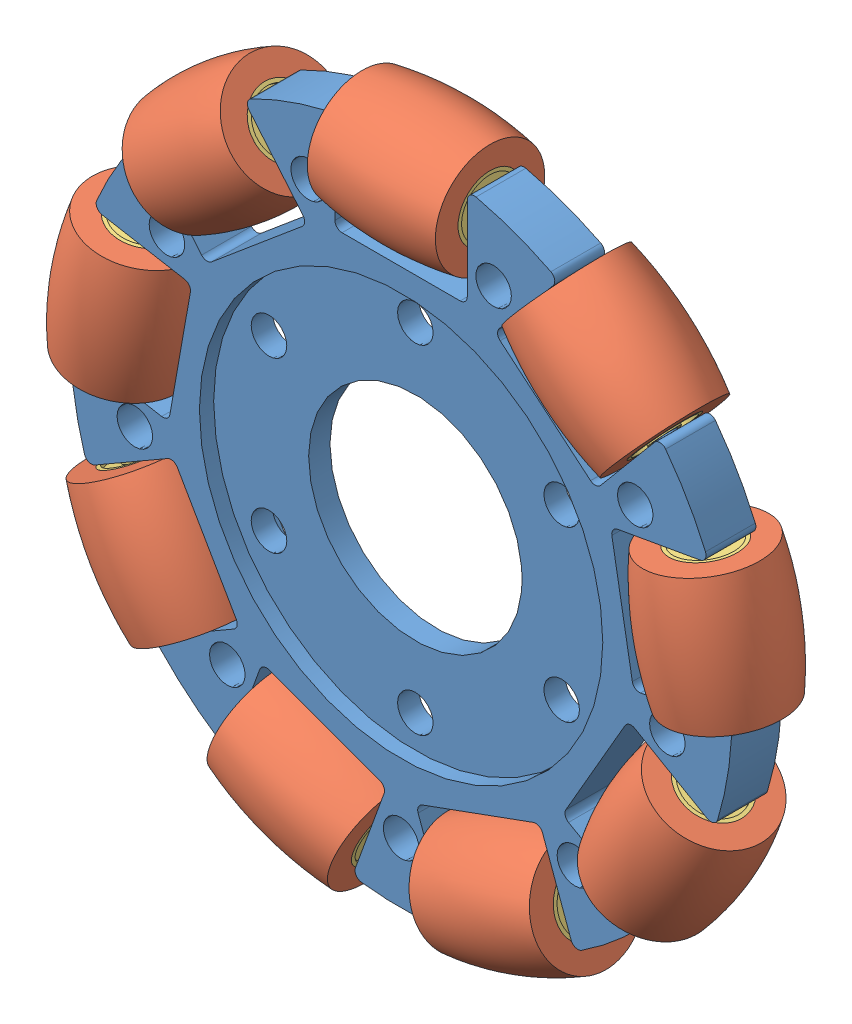
SolidWorks assembly Single Side, configuration Default. Lengths in mm.
Overall size (107.72 106.08 23.21).
28 component instances, 3 part files, 4 mates.
Components (placement in the parent):
- Frame-1: Frame [Default] at origin size (92.88 91.83 7)
- Roller_New-1: Roller_New [預設] at (0 41.5 0) x (1 0 0) z (0 -0.498092 0.867124) size (18 17 17)
- MR93zz_3x9x4mm-1: MR93zz_3x9x4mm [預設] at (7 41.5 0) x (0 0 -1) z (1 0 0) size (9 9 4)
- MR93zz_3x9x4mm-2: MR93zz_3x9x4mm [預設] at (-7 41.5 0) x (0 0 1) z (-1 0 0) size (9 9 4)
- Roller_New-2: Roller_New [預設] at (-26.6757 31.7908 0) x (0.766044 0.642788 0) z (0.320168 -0.381561 0.867124) size (18 17 17)
- Roller_New-3: Roller_New [預設] at (-40.8695 7.2064 0) x (0.173648 0.984808 0) z (0.490525 -0.086493 0.867124) size (18 17 17)
- Roller_New-4: Roller_New [預設] at (-35.9401 -20.75 0) x (-0.5 0.866025 0) z (0.431361 0.249046 0.867124) size (18 17 17)
- Roller_New-5: Roller_New [預設] at (-14.1938 -38.9972 0) x (-0.939693 0.34202 0) z (0.170358 0.468054 0.867124) size (18 17 17)
- Roller_New-6: Roller_New [預設] at (14.1938 -38.9972 0) x (-0.939693 -0.34202 0) z (-0.170358 0.468054 0.867124) size (18 17 17)
- Roller_New-7: Roller_New [預設] at (35.9401 -20.75 0) x (-0.5 -0.866025 0) z (-0.431361 0.249046 0.867124) size (18 17 17)
- Roller_New-8: Roller_New [預設] at (40.8695 7.2064 0) x (0.173648 -0.984808 0) z (-0.490525 -0.086493 0.867124) size (18 17 17)
- Roller_New-9: Roller_New [預設] at (26.6757 31.7908 0) x (0.766044 -0.642788 0) z (-0.320168 -0.381561 0.867124) size (18 17 17)
- MR93zz_3x9x4mm-3: MR93zz_3x9x4mm [預設] at (-32.038 27.2913 0) x (0 0 1) z (-0.766044 -0.642788 0) size (9 9 4)
- MR93zz_3x9x4mm-4: MR93zz_3x9x4mm [預設] at (-42.0851 0.3127 0) x (0 0 1) z (-0.173648 -0.984808 0) size (9 9 4)
- MR93zz_3x9x4mm-5: MR93zz_3x9x4mm [預設] at (-32.4401 -26.8122 0) x (0 0 1) z (0.5 -0.866025 0) size (9 9 4)
- MR93zz_3x9x4mm-6: MR93zz_3x9x4mm [預設] at (-7.616 -41.3914 0) x (0 0 1) z (0.939693 -0.34202 0) size (9 9 4)
- MR93zz_3x9x4mm-7: MR93zz_3x9x4mm [預設] at (20.7717 -36.6031 0) x (0 0 1) z (0.939693 0.34202 0) size (9 9 4)
- MR93zz_3x9x4mm-8: MR93zz_3x9x4mm [預設] at (39.4401 -14.6878 0) x (0 0 1) z (0.5 0.866025 0) size (9 9 4)
- MR93zz_3x9x4mm-9: MR93zz_3x9x4mm [預設] at (39.654 14.1001 0) x (0 0 1) z (-0.173648 0.984808 0) size (9 9 4)
- MR93zz_3x9x4mm-10: MR93zz_3x9x4mm [預設] at (21.3134 36.2904 0) x (0 0 1) z (-0.766044 0.642788 0) size (9 9 4)
- MR93zz_3x9x4mm-11: MR93zz_3x9x4mm [預設] at (-21.3134 36.2904 0) x (0 0 -1) z (0.766044 0.642788 0) size (9 9 4)
- MR93zz_3x9x4mm-12: MR93zz_3x9x4mm [預設] at (-39.654 14.1001 0) x (0 0 -1) z (0.173648 0.984808 0) size (9 9 4)
- MR93zz_3x9x4mm-13: MR93zz_3x9x4mm [預設] at (-39.4401 -14.6878 0) x (0 0 -1) z (-0.5 0.866025 0) size (9 9 4)
- MR93zz_3x9x4mm-14: MR93zz_3x9x4mm [預設] at (-20.7717 -36.6031 0) x (0 0 -1) z (-0.939693 0.34202 0) size (9 9 4)
- MR93zz_3x9x4mm-15: MR93zz_3x9x4mm [預設] at (7.616 -41.3914 0) x (0 0 -1) z (-0.939693 -0.34202 0) size (9 9 4)
- MR93zz_3x9x4mm-16: MR93zz_3x9x4mm [預設] at (32.4401 -26.8122 0) x (0 0 -1) z (-0.5 -0.866025 0) size (9 9 4)
- MR93zz_3x9x4mm-17: MR93zz_3x9x4mm [預設] at (42.0851 0.3127 0) x (0 0 -1) z (0.173648 -0.984808 0) size (9 9 4)
- MR93zz_3x9x4mm-18: MR93zz_3x9x4mm [預設] at (32.038 27.2913 0) x (0 0 -1) z (0.766044 -0.642788 0) size (9 9 4)
Mates (geometry in assembly coordinates):
- 重合/共線/共點1: coincident aligned: circle of Roller_New-1; circle of MR93zz_3x9x4mm-1
- 同軸心1: concentric aligned: cylinder of Frame-1 through (-9.2 41.5 0) axis (1 0 0) radius 1.5; cylinder of Roller_New-1 through (-9 41.5 0) axis (1 0 0) radius 2.5
- 寬度1: width anti-aligned: plane of Frame-1 through (9.3 44.3225 3.5) normal (-1 0 0); plane of Roller_New-1 through (-9.3 32.5376 3.5) normal (1 0 0); plane of Frame-1 through (9 41.5 0) normal (1 0 0); plane of Roller_New-1 through (-9 41.5 0) normal (-1 0 0)
- 重合/共線/共點2: coordinate: point of Frame-1
